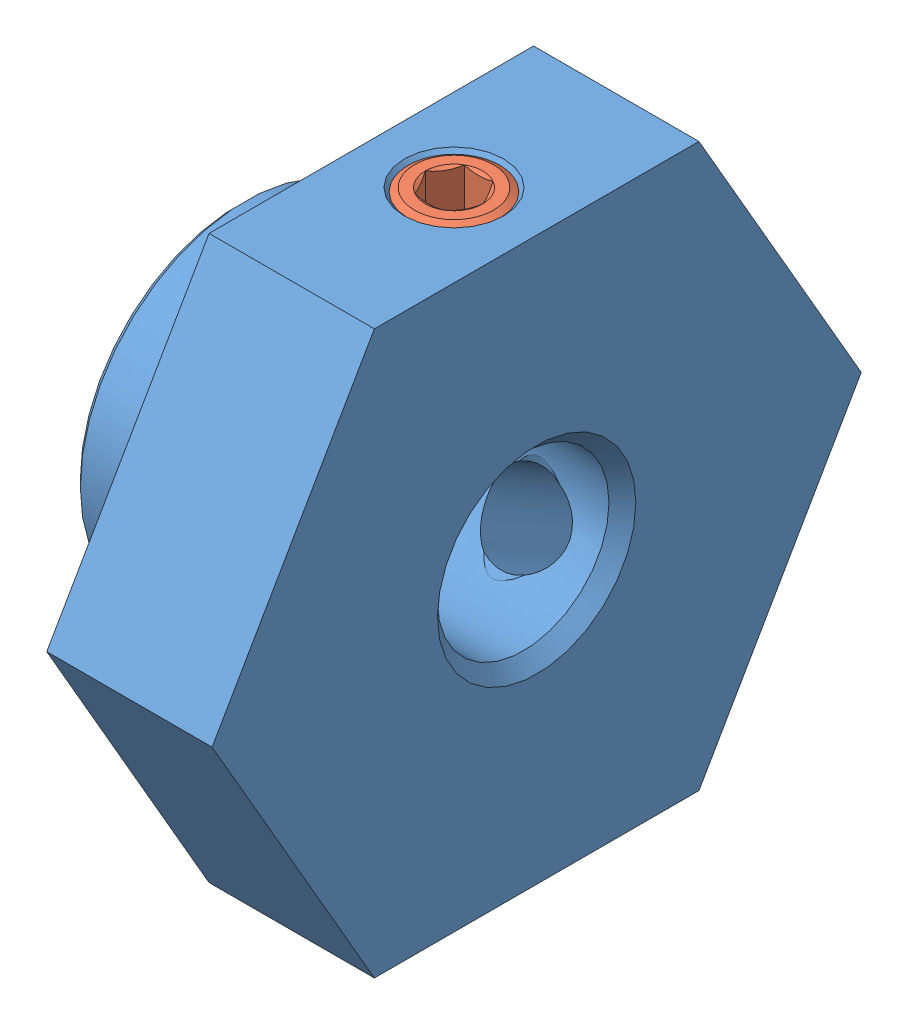
SolidWorks assembly Assem1, configuration Default. Lengths in mm.
Overall size (10.5 17 19.63).
3 component instances, 2 part files, 0 mates.
Components (placement in the parent):
- BNSCS6_part-1: BNSCS6_part [Default] at origin size (9 17 19.63)
- Hexagon_socket_set_screw_with_flat_point_DIN_913___M3x3-1: Hexagon_socket_set_screw_with_flat_point_DIN_913___M3x3 [Default] at (6.5 8.5 0) x (0 -1 0) z (-1 0 0) size (3 3 3)
- Hexagon_socket_set_screw_with_flat_point_DIN_913___M3x3-2: Hexagon_socket_set_screw_with_flat_point_DIN_913___M3x3 [Default] at (6.5 -4.25 -7.3463) x (0 0.5 0.866025) z (-1 0 0) size (3 3 3)
